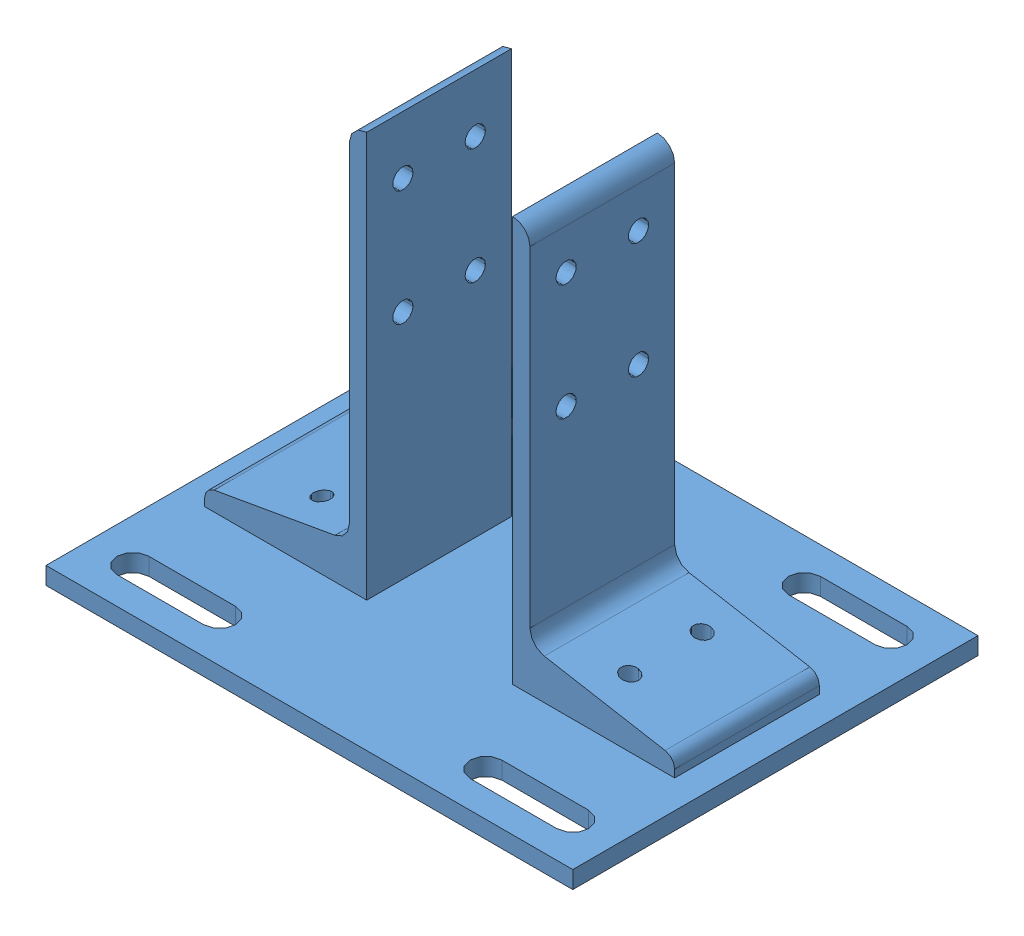
SolidWorks assembly 25_2387, configuration Default. Lengths in mm.
Overall size (182 146 140).
5 component instances, 2 part files, 0 mates.
Components (placement in the parent):
- _25_2387_b_2-1: _25_2387_b_2 [Default] at origin size (182 146 140)
- _M6x1_0_12_s_4-1: _M6x1_0_12_s_4 [Default] at (-53.2 -2.7 12.5) x (0 1 0) z (-1 0 0) size (12 12 12)
- _M6x1_0_12_s_4-2: _M6x1_0_12_s_4 [Default] at (53.2 -2.7 12.5) x (0 1 0) z (-1 0 0) size (12 12 12)
- _M6x1_0_12_s_4-3: _M6x1_0_12_s_4 [Default] at (-53.2 -2.7 -12.5) x (0 1 0) z (-1 0 0) size (12 12 12)
- _M6x1_0_12_s_4-4: _M6x1_0_12_s_4 [Default] at (53.2 -2.7 -12.5) x (0 1 0) z (-1 0 0) size (12 12 12)
